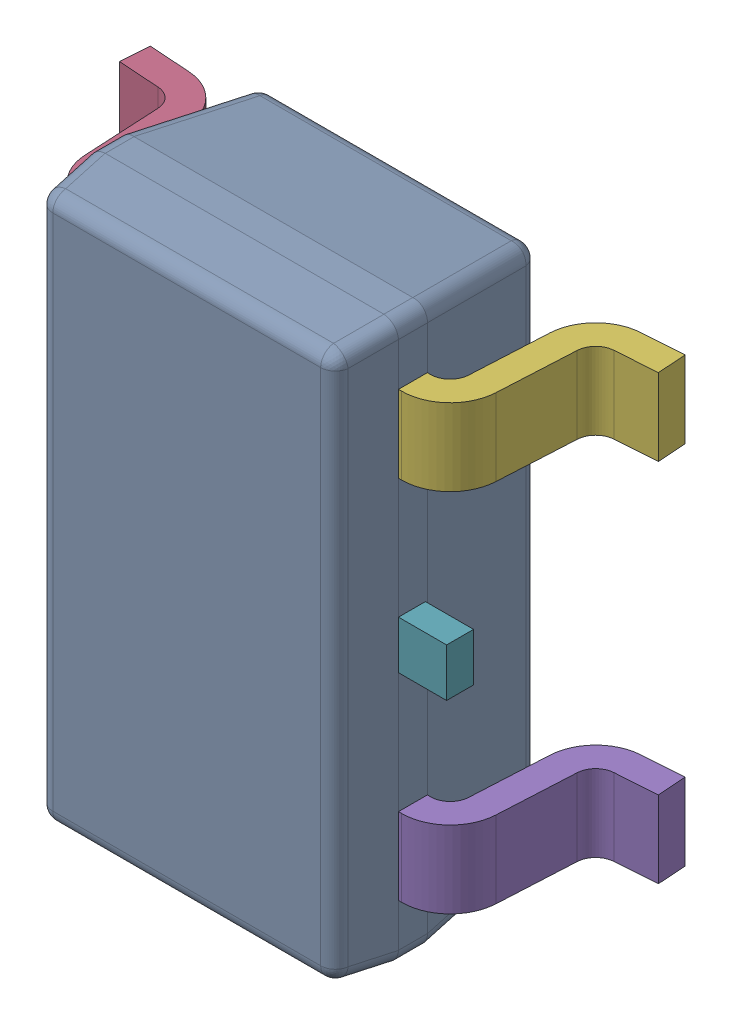
SolidWorks assembly IC19_1.step, configuration Default. Lengths in mm.
Overall size (2.8 2.9 1.2).
8 component instances, 3 part files, 0 mates.
Components (placement in the parent):
- 6348793248_1.step-11: 6348793248_1.step [Default] at (394.3455 305.0466 0) x (1 0 0) z (0 0 1) size (2.8 2.9 1.2)
  - BODY-SOT_1.step-11: BODY-SOT_1.step [Default] at (0 0 0.9) x (0 -1 0) z (-1 0 0) size (2.9 1.1 1.6)
  - LEAD-SOT_1.step-51: LEAD-SOT_1.step [Default] at (-0.9395 -0.95 0.25) x (0 -1 0) z (-1 0 0) size (0.4 0.9 0.6)
  - LEAD-SOT_1.step-52: LEAD-SOT_1.step [Default] at (-0.9395 0 0.25) x (0 -1 0) z (-1 0 0) size (0.4 0.9 0.6)
  - LEAD-SOT_1.step-53: LEAD-SOT_1.step [Default] at (-0.9395 0.95 0.25) x (0 -1 0) z (-1 0 0) size (0.4 0.9 0.6)
  - LEAD-SOT_1.step-54: LEAD-SOT_1.step [Default] at (0.9395 -0.95 0.25) x (0 1 0) z (1 0 0) size (0.4 0.9 0.6)
  - LEAD-SOT_1.step-55: LEAD-SOT_1.step [Default] at (0.9395 0.95 0.25) x (0 1 0) z (1 0 0) size (0.4 0.9 0.6)
  - LEAD-DUMMY_1.step-11: LEAD-DUMMY_1.step [Default] at (1.05 0 0.76) x (0 -1 0) z (-1 0 0) size (0.25 0.14 0.25)
